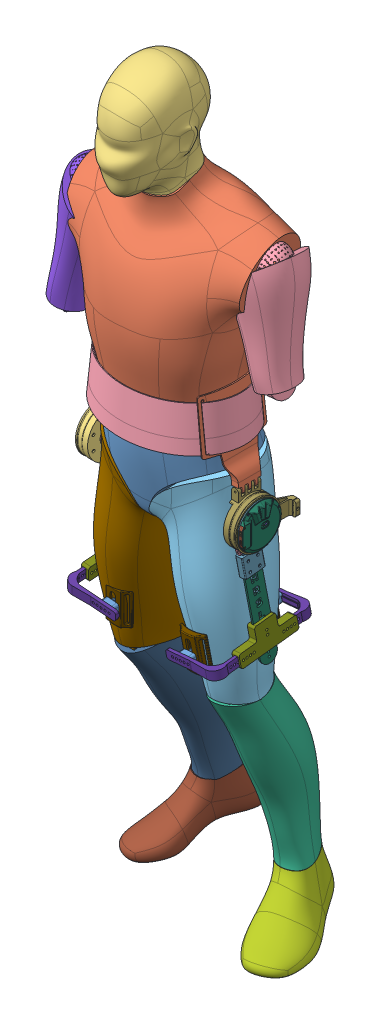
SolidWorks assembly MannequinWithExo, configuration Default. Lengths in mm.
Overall size (752.77 1773.03 490.09).
73 component instances, 39 part files, 1 mates.
Components (placement in the parent):
- Manikin1.STEP-1: Manikin1.STEP [Default] at (760.6869 -2689.0648 1266.7674) size (778.05 1773.03 504.23)
  - Hips.STEP-1: Hips.STEP [Default] at origin size (284.89 311.18 251.14)
  - Torso.STEP-1: Torso.STEP [Default] at (-29.1895 18.5281 -268.9557) x (0.995716 0.002037 -0.092438) z (0.092349 -0.071067 0.993187) size (460.89 555.97 263.41)
  - Head.STEP-1: Head.STEP [Default] at (-35.3994 3.8201 -64.7195) x (0.99996 -0.00842 0.002952) z (-0.003142 -0.022585 0.99974) size (157.49 285.21 225.45)
  - ArmLeftUpper.STEP-1: ArmLeftUpper.STEP [Default] at (-2789.9904 1354.2797 -616.211) x (0.699144 -0.708077 0.099124) z (-0.173701 -0.033728 0.984221) size (245.85 237.32 159.1)
  - LegLeftUpper.STEP-1: LegLeftUpper.STEP [Default] at (-348.9145 19.2317 91.8942) x (0.994631 -0.095632 -0.039543) z (0.041707 0.020745 0.998914) size (214.8 507.99 232.7)
  - ArmLeftFore.STEP-1: ArmLeftFore.STEP [Default] at (-2774.6323 1365.4227 -714.6365) x (0.707626 -0.704894 0.048893) z (-0.158512 -0.090931 0.983161) size (231.54 175.95 140.74) (hidden)
  - ArmLeftHand.STEP-1: ArmLeftHand.STEP [Default] at (-1936.929 562.4053 -725.019) x (0.885934 -0.459942 0.059786) z (-0.134029 -0.130474 0.982351) size (149.66 182.81 146.49) (hidden)
  - LegLeftLower.STEP-1: LegLeftLower.STEP [Default] at (-365.2346 49.792 -328.4023) x (0.9943 -0.09526 -0.047882) z (0.037349 -0.109435 0.993292) size (165.7 443.66 192.39)
  - LegLeftFoot.STEP-1: LegLeftFoot.STEP [Default] at (-360.4265 38.9625 -201.844) x (0.994403 -0.095494 -0.045215) z (0.039103 -0.064928 0.997123) size (149.76 147.12 252.53)
  - ArmRightUpper.STEP-1: ArmRightUpper.STEP [Default] at (2833.3521 1349.4619 519.7345) x (0.711137 0.701856 -0.04102) z (-0.054094 0.112795 0.992145) size (246.03 237.34 159.02)
  - ArmRightFore.STEP-1: ArmRightFore.STEP [Default] at (2854.7947 1351.048 269.4164) x (0.701784 0.707122 0.08647) z (-0.091697 -0.030706 0.995313) size (231.51 175.94 140.81) (hidden)
  - ArmRightHand.STEP-1: ArmRightHand.STEP [Default] at (1627.5665 608.1197 -1273.5362) x (0.931008 0.283533 0.229854) z (-0.087727 -0.437455 0.894951) size (149.56 182.72 146.39) (hidden)
  - LegRightUpper.STEP-1: LegRightUpper.STEP [Default] at (424.7777 28.5767 78.6764) x (0.990444 0.116021 0.074569) z (-0.076432 0.011681 0.997006) size (214.82 507.94 232.64)
  - LegRightLower.STEP-1: LegRightLower.STEP [Default] at (485.8552 172.4048 -823.1357) x (0.989203 0.113669 0.092505) z (-0.05906 -0.26849 0.96147) size (165.71 450.95 192.39)
  - LegRightFoot.STEP-1: LegRightFoot.STEP [Default] at (465.2648 103.2633 -505.3548) x (0.989637 0.115132 0.085807) z (-0.067206 -0.156695 0.985358) size (149.76 152.18 252.53)
- FullExoAssemL_v1-1: FullExoAssemL_v1 [Default] at (959.8599 883.6876 1505.2362) x (-1 0 0) z (0 0 -1) size (138.21 569.68 234.57)
  - MotorHousingL_v3-1: MotorHousingL_v3 [Default] at (45.6214 50.3141 116.6369) x (0 0 -1) z (1 0 0) size (136.17 126 49)
  - RotorAttachCanted_v2-1: RotorAttachCanted_v2 [Default] at (25.6214 50.3141 116.6369) x (0 -0.113584 -0.993528) z (1 0 0) size (40 90 16)
  - ThighHinge-1: ThighHinge [Default] at (32.9361 -19.972 124.8736) x (0 -0.113584 -0.993528) z (-0.995056 0.098671 -0.01128) size (46.2 56 16)
  - ThighVertAdjust_v1-1: ThighVertAdjust_v1 [Default] at (9.6957 -245.3515 150.3378) x (0 -0.113584 -0.993528) z (0.995056 -0.098671 0.01128) size (40 225 4)
  - ThighTShape_v2-1: ThighTShape_v2 [Default] at (6.9232 -184.9431 143.1801) x (0 -0.113584 -0.993528) z (0.995056 -0.098671 0.01128) size (134 60 17)
  - Lshape-thigh-1: Lshape-thigh [Default] at (124.8422 -209.4318 253.7869) x (-0.995056 0.098671 -0.01128) z (0 -0.113584 -0.993528) size (119.06 20 70.06)
  - sliding_mechanism-1: sliding_mechanism [Default] at (121.677 -229.1089 229.1491) x (-0.995056 0.098671 -0.01128) z (0 -0.113584 -0.993528) size (60 80 31.83)
    - slide1-2: slide1 [Default] at (35.9132 -9.9128 77.9746) size (60 80 19.04)
    - slide2_centered-2: slide2_centered [Default] at (35.9132 26.7329 3.1866) x (-1 0 0) z (0 0 -1) size (30 20 23)
  - Lshape-thigh-2: Lshape-thigh [Default] at (126.8284 -215.3693 26.639) x (-0.995056 0.098671 -0.01128) z (0 0.113584 0.993528) size (119.06 20 70.06)
  - sliding_mechanism-2: sliding_mechanism [Default] at (50.6553 -241.7078 56.5375) x (0.995056 -0.098671 0.01128) z (0 0.113584 0.993528) size (60 80 31.83)
    - slide1-2: slide1 [Default] at (35.9132 -9.9128 77.9746) size (60 80 19.04)
    - slide2_centered-2: slide2_centered [Default] at (35.9132 26.7329 3.1866) x (-1 0 0) z (0 0 -1) size (30 20 23)
  - MotorHipAttach-2: MotorHipAttach [Default] at (29.6214 115.3141 117.118) x (0 0 1) z (-0.997763 0.066849 0) size (149.69 202 38.03)
- ThighAssem_v3-1: ThighAssem_v3 [Default] at (538.4225 849.514 1248.9326) size (146.98 576.85 206.34)
  - MotorHousingR_v2-1: MotorHousingR_v2 [Default] at (55.5071 74.2288 116.9013) x (0 0 1) z (-1 0 0) size (136.17 126 49)
  - RotorAttachCanted_v2-1: RotorAttachCanted_v2 [Default] at (51.5071 74.2288 116.9013) x (0 0.078125 -0.996944) z (1 0 0) size (40 90 16)
  - ThighVertAdjust_v1-1: ThighVertAdjust_v1 [Default] at (39.2525 -223.2998 93.3851) x (0 0.078125 -0.996944) z (0.996365 -0.084931 -0.006656) size (40 225 4)
  - ThighHinge-1: ThighHinge [Default] at (58.918 3.6567 111.1704) x (0 0.078125 -0.996944) z (-0.996365 0.084931 0.006656) size (46.2 56 16)
  - ThighTShape_v2-1: ThighTShape_v2 [Default] at (35.252 -166.9254 97.3013) x (0 0.078125 -0.996944) z (0.996365 -0.084931 -0.006656) size (134 60 17)
  - MotorHipAttach-1: MotorHipAttach [Default] at (55.5071 139.2288 117.3823) x (0 0 1) z (-0.995685 0.092797 0) size (149.69 202 38.03)
  - Lshape-thigh-1: Lshape-thigh [Default] at (153.6823 -210.5982 203.8246) x (-0.996365 0.084931 0.006656) z (0 0.078125 -0.996944) size (119.06 20 70.06)
  - Lshape-thigh-2: Lshape-thigh [Default] at (155.3861 -175.2248 7.4969) x (-0.996365 0.084931 0.006656) z (0 -0.078125 0.996944) size (119.06 20 70.06)
  - sliding_mechanism-1: sliding_mechanism [Default] at (88.7366 -208.6348 31.674) x (0.996365 -0.084931 -0.006656) z (0 -0.078125 0.996944) size (60 80 31.83)
    - slide1-2: slide1 [Default] at (35.9132 -9.9128 77.9746) size (60 80 19.04)
    - slide2_centered-2: slide2_centered [Default] at (35.9132 26.7329 3.1866) x (-1 0 0) z (0 0 -1) size (30 20 23)
  - sliding_mechanism-2: sliding_mechanism [Default] at (94.969 -166.948 180.3497) x (0.996365 -0.084931 -0.006656) z (0 0.078125 -0.996944) size (60 80 31.83)
    - slide1-2: slide1 [Default] at (35.9132 -9.9128 77.9746) size (60 80 19.04)
    - slide2_centered-2: slide2_centered [Default] at (35.9132 26.7329 3.1866) x (-1 0 0) z (0 0 -1) size (30 20 23)
- WaistStrap-1: WaistStrap [Default] at (766.4849 1127.713 1387.5828) size (320.01 99.79 260.01)
- 202011-ActPack-Geared.STEP-1: 202011-ActPack-Geared.STEP [Default] at (957.8855 934.0017 1388.5993) x (0 0 -1) z (1 0 0) size (98 98 42.51)
  - AK80-9 3D.STEP-1: AK80-9 3D.STEP [Default] at (0 -501.6085 -756.5855) x (0 0 1) z (-1 0 0) size (28.5 98 98)
    - AK80-9 3D(2)^AK80-9 3D.STEP-1: AK80-9 3D(2)^AK80-9 3D.STEP [Default] at origin size (28.5 98 98)
      - AK80-9_ASM_ASM^AK80-9 3D(2)_AK80-9 3D.STEP-1: AK80-9_ASM_ASM^AK80-9 3D(2)_AK80-9 3D.STEP [Default] at origin size (28.5 98 98)
        - PRODUCT_46766_ASM_ASM^AK80-9_ASM_ASM_AK80-9 3D(2)_AK80-9 3D.STEP-1: PRODUCT_46766_ASM_ASM^AK80-9_ASM_ASM_AK80-9 3D(2)_AK80-9 3D.STEP [Default] at origin size (28.5 98 98)
          - ____5^PRODUCT_46766_ASM_ASM_AK80-9_ASM_ASM_AK80-9 3D(2)_AK80-9 3D.STEP-1: ____5^PRODUCT_46766_ASM_ASM_AK80-9_ASM_ASM_AK80-9 3D(2)_AK80-9 3D.STEP [Default] at origin size (7.5 37 37)
          - ____1^PRODUCT_46766_ASM_ASM_AK80-9_ASM_ASM_AK80-9 3D(2)_AK80-9 3D.STEP-1: ____1^PRODUCT_46766_ASM_ASM_AK80-9_ASM_ASM_AK80-9 3D(2)_AK80-9 3D.STEP [Default] at origin size (2 14 14)
          - ____2^PRODUCT_46766_ASM_ASM_AK80-9-MODIFIED-20201030.STEP-1: ____2^PRODUCT_46766_ASM_ASM_AK80-9-MODIFIED-20201030.STEP [Default] at origin size (6 98 98)
          - ____7^PRODUCT_46766_ASM_ASM_AK80-9_ASM_ASM_AK80-9 3D(2)_AK80-9 3D.STEP-1: ____7^PRODUCT_46766_ASM_ASM_AK80-9_ASM_ASM_AK80-9 3D(2)_AK80-9 3D.STEP [Default] at origin size (24.23 98 98)
  - RIGID_4_1_USB_0_1.STEP-1: RIGID_4_1_USB_0_1.STEP [Default] at (-43.9 -8.8349 6.09) x (0 -1 0) z (0 0 1) size (12.35 9.94 4.02)
    - RIGID_4_1_USB_0_1(2)^RIGID_4_1_USB_0_1.STEP-1: RIGID_4_1_USB_0_1(2)^RIGID_4_1_USB_0_1.STEP [Default] at origin size (12.35 9.94 4.02)
      - J1^RIGID_4_1_USB_0_1(2)_RIGID_4_1_USB_0_1.STEP-1: J1^RIGID_4_1_USB_0_1(2)_RIGID_4_1_USB_0_1.STEP [Default] at origin size (12.35 9.94 4.02)
        - CUI_DEVICES_UJ31-CH-3-MSMT-TR-67(2)^J1_RIGID_4_1_USB_0_1(2)_RIGID_4_1_USB_0_1.STEP-1: CUI_DEVICES_UJ31-CH-3-MSMT-TR-67(2)^J1_RIGID_4_1_USB_0_1(2)_RIGID_4_1_USB_0_1.STEP [Default] at (4.6001 0.25 0.31) x (0 1 0) z (1 0 0) size (9.94 4.02 12.35)
  - APL_P003_V41_MOUNTCOVER_MB.STEP-1: APL_P003_V41_MOUNTCOVER_MB.STEP [Default] at origin size (96 98 15.01)
  - APL_P004_V41_USBMOUNT_MB.STEP-1: APL_P004_V41_USBMOUNT_MB.STEP [Default] at (-47 22.0077 2.5) x (0 -1 0) z (0 0 1) size (44.02 7.7 7.3)
  - FX_P001_V41_RIGID_LUMP.STEP-1: FX_P001_V41_RIGID_LUMP.STEP [Default] at (-39.0889 -43.5 3.51) x (1 0 0) z (0 0 1) size (13.96 13.31 8.46)
  - PLP2-100.STEP-1: PLP2-100.STEP [Default] at (5.21 0 1.7962) size (3.3 3.3 3.26)
  - APL_P001_V41_MOUNT.STEP-1: APL_P001_V41_MOUNT.STEP [Default] at origin size (96 98 2.5)
  - APL_P002_V41_COVER.STEP-1: APL_P002_V41_COVER.STEP [Default] at origin size (96 98 12.52)
  - 90236A106_ METRIC ALLOY STEEL TORX FLAT HEAD SCREWS (1)_90236A106.STEP-1: 90236A106_ METRIC ALLOY STEEL TORX FLAT HEAD SCREWS (1)_90236A106.STEP [Default] at (-42.05 19.2577 11.1) size (3.8 3.8 0.9)
  - 90236A106_ METRIC ALLOY STEEL TORX FLAT HEAD SCREWS (1)_90236A106.STEP-2: 90236A106_ METRIC ALLOY STEEL TORX FLAT HEAD SCREWS (1)_90236A106.STEP [Default] at (-42.05 -19.2577 11.1) size (3.8 3.8 0.9)
  - 90910A920_LOW-PROFILE BUTTON HEAD TORX MACHINE SCREW (1)_90910A920.STEP-1: 90910A920_LOW-PROFILE BUTTON HEAD TORX MACHINE SCREW (1)_90910A920.STEP [Default] at (0 -46.25 5.5) size (3.8 3.8 1.1)
  - 90910A920_LOW-PROFILE BUTTON HEAD TORX MACHINE SCREW (1)_90910A920.STEP-2: 90910A920_LOW-PROFILE BUTTON HEAD TORX MACHINE SCREW (1)_90910A920.STEP [Default] at (42.05 -19.2577 5.5) x (0.987351 0.158553 0) z (0 0 1) size (3.8 3.8 1.1)
  - 90910A920_LOW-PROFILE BUTTON HEAD TORX MACHINE SCREW (1)_90910A920.STEP-3: 90910A920_LOW-PROFILE BUTTON HEAD TORX MACHINE SCREW (1)_90910A920.STEP [Default] at (42.05 19.2577 5.5) x (0.959125 0.282984 0) z (0 0 1) size (3.8 3.8 1.1)
  - 90910A920_LOW-PROFILE BUTTON HEAD TORX MACHINE SCREW (1)_90910A920.STEP-4: 90910A920_LOW-PROFILE BUTTON HEAD TORX MACHINE SCREW (1)_90910A920.STEP [Default] at (28 36.8112 5.5) x (0.928571 0.371154 0) z (0 0 1) size (3.8 3.8 1.1)
  - 90910A920_LOW-PROFILE BUTTON HEAD TORX MACHINE SCREW (1)_90910A920.STEP-5: 90910A920_LOW-PROFILE BUTTON HEAD TORX MACHINE SCREW (1)_90910A920.STEP [Default] at (-28 36.8112 5.5) x (0.906989 0.421154 0) z (0 0 1) size (3.8 3.8 1.1)
Mates (geometry in assembly coordinates):
- Concentric1: concentric anti-aligned: cylinder of FullExoAssemL_v1-1/MotorHousingL_v3-1 through (934.2385 934.0017 1388.5993) axis (1 0 0) radius 50.25; cylinder of 202011-ActPack-Geared.STEP-1/AK80-9 3D.STEP-1/AK80-9 3D(2)^AK80-9 3D.STEP-1/AK80-9_ASM_ASM^AK80-9 3D(2)_AK80-9 3D.STEP-1/PRODUCT_46766_ASM_ASM^AK80-9_ASM_ASM_AK80-9 3D(2)_AK80-9 3D.STEP-1/____7^PRODUCT_46766_ASM_ASM_AK80-9_ASM_ASM_AK80-9 3D(2)_AK80-9 3D.STEP-1 through (944.8855 934.0017 1388.5993) axis (-1 0 0) radius 49
